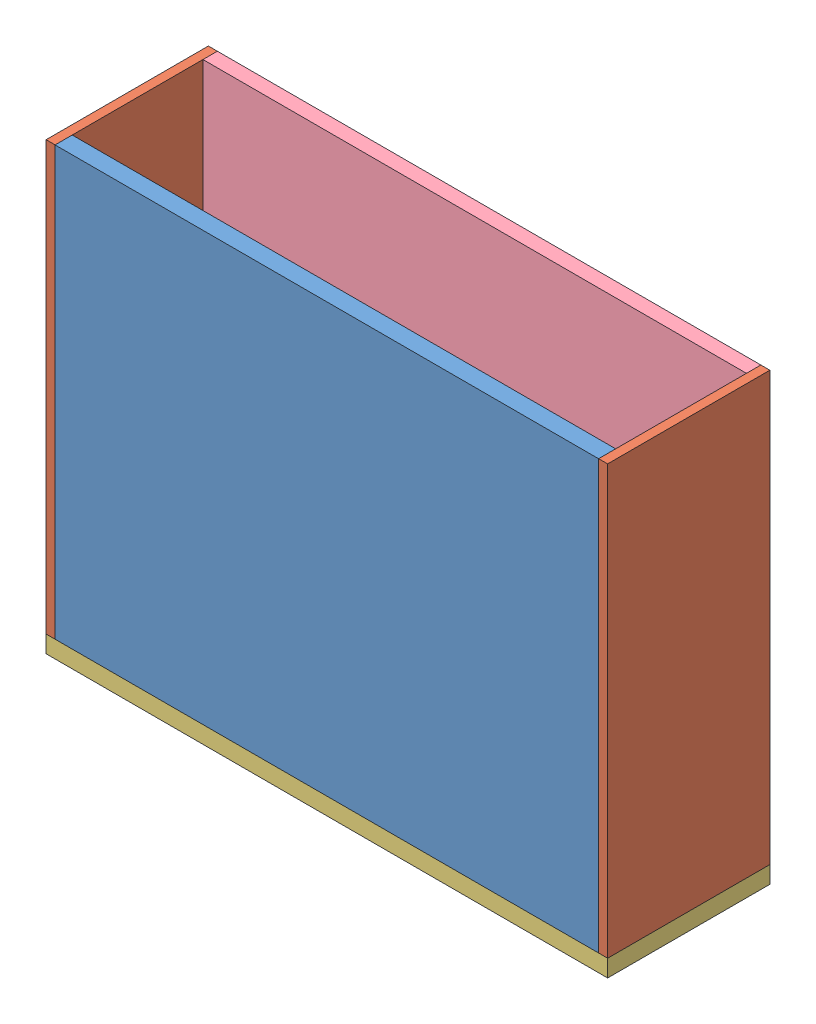
SolidWorks assembly Box_unten, configuration Standard. Lengths in mm.
Overall size (623 494 180.09).
5 component instances, 4 part files, 12 mates.
Components (placement in the parent):
- Platte-2: Platte [Standard] at (-36.5959 0.0034 956) x (1 0 0) z (0 -0.00018 1) size (603 475 19)
- Box_Seitenteil-2: Box_Seitenteil [Standard] at (274.9041 0 884.9572) x (0 -1 0) z (-1 0 0) size (475 180 10)
- Box_Seitenteil-3: Box_Seitenteil [Standard] at (-338.0959 0 884.9572) x (0 1 0) z (-1 0 0) size (475 180 10)
- Seitenteil_lang-1: Seitenteil_lang [Standard] at (-36.5959 -256.5 884.9572) x (1 0 0) z (0 1 0) size (623 180 19)
- Platte16mm-1: Platte16mm [Standard] at (-36.5959 0 794.9572) size (603 475 16)
Mates (geometry in assembly coordinates):
- Deckungsgleich2: coincident anti-aligned: plane of Platte-2 through (264.9041 -138.673 975) normal (1 0 0); plane of Box_Seitenteil-2 through (264.9041 98.8108 884.9572) normal (-1 0 0)
- Deckungsgleich3: coincident: point of Box_Seitenteil-2; point of Seitenteil_lang-1
- Deckungsgleich4: coincident: point of Platte-2; point of Box_Seitenteil-2
- Deckungsgleich7: coincident: point of Box_Seitenteil-2; point of Seitenteil_lang-1
- Deckungsgleich8: coincident: point of Box_Seitenteil-3; point of Seitenteil_lang-1
- Parallel2: parallel aligned: plane of Box_Seitenteil-3 through (-348.0959 98.8108 884.9572) normal (-1 0 0); plane of Seitenteil_lang-1 through (-348.0959 -138.673 975) normal (-1 0 0)
- Deckungsgleich10: coincident anti-aligned: plane of Box_Seitenteil-2 through (264.9041 98.8108 884.9572) normal (-1 0 0); plane of Platte16mm-1 through (264.9041 -138.7026 811) normal (1 0 0)
- Deckungsgleich12: coincident anti-aligned: plane of Box_Seitenteil-3 through (-338.0959 98.8108 884.9572) normal (1 0 0); plane of Platte16mm-1 through (-338.0959 -138.7026 811) normal (-1 0 0)
- Parallel3: parallel aligned: plane of Box_Seitenteil-3 through (-348.0959 336.2945 794.9144) normal (0 -0.00018 -1); plane of Platte16mm-1 through (-36.5959 98.7946 794.9572) normal (0 -0.00018 -1)
- Deckungsgleich13: coincident aligned: plane of Box_Seitenteil-3 through (-348.0959 336.2945 794.9144) normal (0 -0.00018 -1); plane of Platte16mm-1 through (-36.5959 98.7946 794.9572) normal (0 -0.00018 -1)
- Deckungsgleich14: coincident anti-aligned: plane of Seitenteil_lang-1 through (-36.5959 -138.6892 885) normal (0 1 -0.00018); plane of Platte16mm-1 through (264.9041 -138.7026 811) normal (0 -1 0.00018)
- Deckungsgleich15: coincident aligned: unknown of Platte16mm-1
